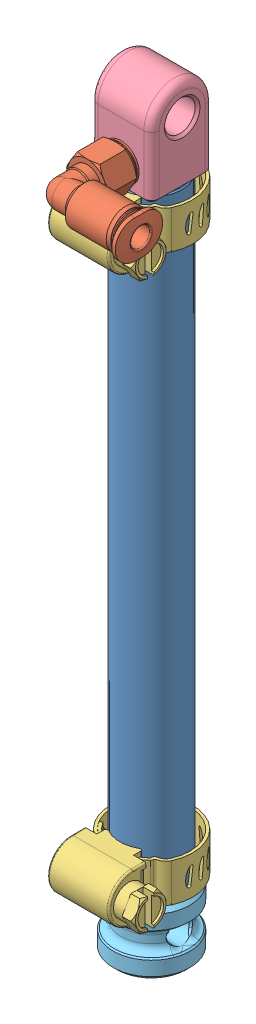
SolidWorks assembly AARL_QR_PN_PA_FR_WR_FL-Flexor, configuration Default. Lengths in mm.
Overall size (24.22 158.75 31.28).
6 component instances, 5 part files, 15 mates.
Components (placement in the parent):
- AARL_QR_PN_PA_FR_WR_FL_001-1: AARL_QR_PN_PA_FR_WR_FL_001 [Resting] at origin size (12.7 127 12.7)
- AARL_Puppy_18_02_57_010-QSML-M3-4-1: AARL_Puppy_18_02_57_010-QSML-M3-4 [Default] at (0 68.2625 17.85) x (1 0 0) z (0 0 -1) size (20.32 8 18.9)
- AARL_Puppy_18_02_57_011-5388K140_Hose-Clamp-1: AARL_Puppy_18_02_57_011-5388K140_Hose-Clamp [5388K14] at (0 -58.547 0) x (1 0 0) z (0 -1 0) size (19.43 23.71 9.91)
- AARL_Puppy_18_02_57_011-5388K140_Hose-Clamp-2: AARL_Puppy_18_02_57_011-5388K140_Hose-Clamp [5388K14] at (0 58.547 0) x (1 0 0) z (0 -1 0) size (19.43 23.71 9.91)
- AARL_QR_PN_EP_001-1: AARL_QR_PN_EP_001 [Default] at (0 76.2 0) x (0 0 1) z (-1 0 0) size (12.7 31.75 12.7)
- AARL_QR_PN_EP_002-1: AARL_QR_PN_EP_002 [Default] at (0 -63.5 0) x (-1 0 0) z (0 0 1) size (15.88 25.4 15.88)
Mates (geometry in assembly coordinates):
- Concentric1: concentric aligned: cylinder of AARL_QR_PN_PA_FR_WR_FL_001-1 through (0 11.6086 0) axis (0 1 0) radius 4.7625; cylinder of AARL_QR_PN_EP_001-1 through (0 85.744 0) axis (0 1 0) radius 4.3656
- Parallel1: parallel aligned: plane of AARL_QR_PN_EP_001-1 through (-6.35 63.5 6.35) normal (0 0 1)
- Coincident2: coincident anti-aligned: plane of AARL_QR_PN_PA_FR_WR_FL_001-1 through (4.7625 63.5 0) normal (0 1 0); plane of AARL_QR_PN_EP_001-1 through (-6.35 63.5 -6.35) normal (0 -1 0)
- Concentric2: concentric anti-aligned: cylinder of AARL_QR_PN_PA_FR_WR_FL_001-1 through (0 11.6086 0) axis (0 1 0) radius 4.7625; cylinder of AARL_QR_PN_EP_002-1 through (0 -71.2377 0) axis (0 -1 0) radius 4.3656
- Coincident3: coincident anti-aligned: plane of AARL_QR_PN_PA_FR_WR_FL_001-1 through (6.35 -63.5 0) normal (0 -1 0); plane of AARL_QR_PN_EP_002-1 through (-4.3656 -63.5 0) normal (0 1 0)
- Parallel2: parallel anti-aligned: cylinder of AARL_QR_PN_EP_001-1 through (-6.35 76.2 0) axis (1 0 0) radius 3.175; cylinder of AARL_QR_PN_EP_002-1 through (7.9375 -69.85 0) axis (-1 0 0) radius 2.3813
- Concentric4: concentric aligned: cylinder of AARL_Puppy_18_02_57_010-QSML-M3-4-1 through (0 68.2625 6.35) axis (0 0 1) radius 1.5; cylinder of AARL_QR_PN_EP_001-1 through (0 68.2625 6.35) axis (0 0 1) radius 2.0193
- Coincident4: coincident anti-aligned: plane of AARL_Puppy_18_02_57_010-QSML-M3-4-1 through (0 68.2625 6.35) normal (0 0 -1); plane of AARL_QR_PN_EP_001-1 through (-6.35 63.5 6.35) normal (0 0 1)
- Parallel3: parallel anti-aligned: plane of AARL_Puppy_18_02_57_010-QSML-M3-4-1 through (-2.3094 72.2625 13.4056) normal (0 1 0); plane of AARL_QR_PN_EP_001-1 through (-6.35 63.5 -6.35) normal (0 -1 0)
- Concentric5: concentric aligned: cylinder of AARL_QR_PN_PA_FR_WR_FL_001-1 through (0 11.6086 0) axis (0 1 0) radius 6.35; cylinder of AARL_Puppy_18_02_57_011-5388K140_Hose-Clamp-2 through (0 54.5783 0) axis (0 1 0) radius 7.9375
- Coincident6: coincident aligned: plane of AARL_Puppy_18_02_57_011-5388K140_Hose-Clamp-2 through (6.35 58.547 10.2337) normal (1 0 0); plane of AARL_QR_PN_EP_001-1 through (6.35 76.2 0) normal (1 0 0)
- Coincident7: coincident anti-aligned: plane of AARL_Puppy_18_02_57_011-5388K140_Hose-Clamp-2 through (0 63.5 0) normal (0 1 0); plane of AARL_QR_PN_EP_001-1 through (-6.35 63.5 -6.35) normal (0 -1 0)
- Concentric6: concentric aligned: cylinder of AARL_QR_PN_PA_FR_WR_FL_001-1 through (0 11.6086 0) axis (0 1 0) radius 6.35; cylinder of AARL_Puppy_18_02_57_011-5388K140_Hose-Clamp-1 through (0 -62.5157 0) axis (0 1 0) radius 7.9375
- Coincident8: coincident aligned: plane of AARL_Puppy_18_02_57_011-5388K140_Hose-Clamp-1 through (6.35 -58.547 10.2337) normal (1 0 0); plane of AARL_Puppy_18_02_57_011-5388K140_Hose-Clamp-2 through (6.35 58.547 10.2337) normal (1 0 0)
- Coincident9: coincident anti-aligned: plane of AARL_Puppy_18_02_57_011-5388K140_Hose-Clamp-1 through (0 -63.5 0) normal (0 -1 0); plane of AARL_QR_PN_EP_002-1 through (-4.3656 -63.5 0) normal (0 1 0)
